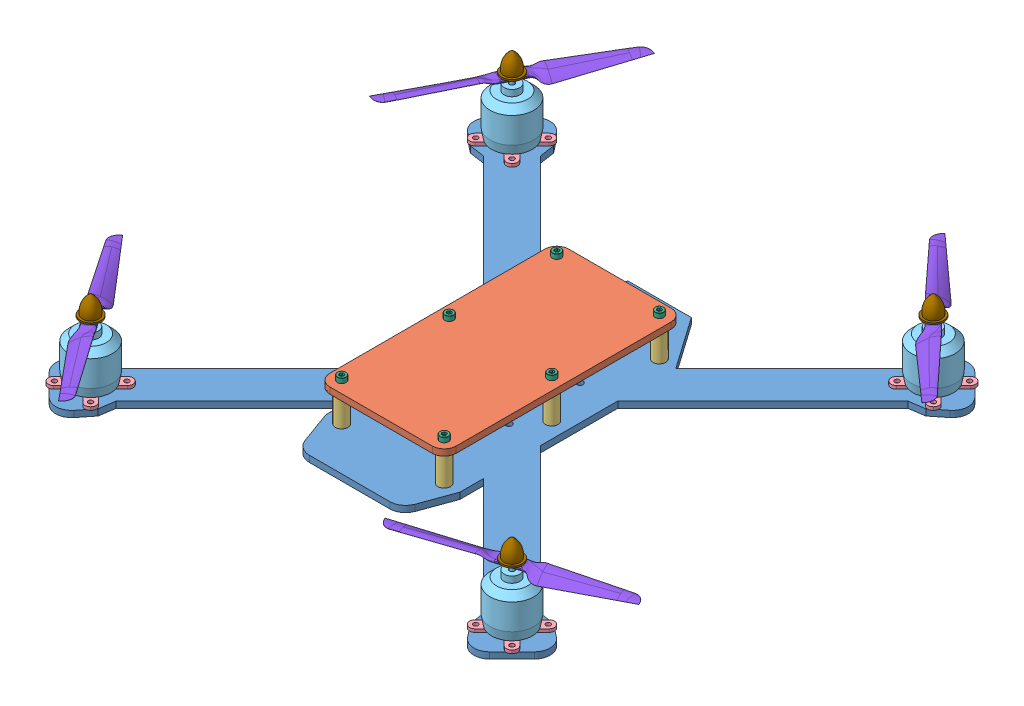
SolidWorks assembly DroneQuadV2, configuration Predeterminado. Lengths in mm.
Overall size (377.34 57 387.09).
52 component instances, 9 part files, 113 mates.
Components (placement in the parent):
- DroneChassisV2-1: DroneChassisV2 [Predeterminado] at origin size (313.31 4 313.31)
- TapaDronV2-1: TapaDronV2 [Predeterminado] at (0 24 0) size (80 4 151.37)
- Soporte-1: Soporte [Predeterminado] at (-32.5 4 -60.9077) x (-0.782804 0 0.622268) z (-0.622268 0 -0.782804) size (8 20 8)
- Soporte-2: Soporte [Predeterminado] at (-32.5 4 7.2764) x (0.196704 0 0.980463) z (-0.980463 0 0.196704) size (8 20 8)
- Soporte-3: Soporte [Predeterminado] at (-32.5 4 75.4605) x (0.051927 0 -0.998651) z (0.998651 0 0.051927) size (8 20 8)
- Soporte-5: Soporte [Predeterminado] at (32.5 4 7.2764) x (0.261502 0 0.965203) z (-0.965203 0 0.261502) size (8 20 8)
- Soporte-6: Soporte [Predeterminado] at (32.5 4 -60.9077) x (0.15369 0 0.988119) z (-0.988119 0 0.15369) size (8 20 8)
- BrushlessMount-1: BrushlessMount [Predeterminado] at (133.527 4 133.527) x (0.707107 0 0.707107) z (-0.707107 0 0.707107) size (40 2 40)
- BrushlessMount-2: BrushlessMount [Predeterminado] at (133.527 4 -133.527) x (0.707107 0 -0.707107) z (0.707107 0 0.707107) size (40 2 40)
- BrushlessMount-3: BrushlessMount [Predeterminado] at (-133.527 4 -133.527) x (0.707107 0 0.707107) z (-0.707107 0 0.707107) size (40 2 40)
- BrushlessMount-4: BrushlessMount [Predeterminado] at (-133.527 4 133.527) x (0.707107 0 -0.707107) z (0.707107 0 0.707107) size (40 2 40)
- MotorBrushless-1: MotorBrushless [Predeterminado] at (-133.527 6 -133.527) x (0.707107 0 0.707107) z (-0.707107 0 0.707107) size (27.7 40 27.7)
- MotorBrushless-2: MotorBrushless [Predeterminado] at (-133.527 6 133.527) x (0.707107 0 -0.707107) z (0.707107 0 0.707107) size (27.7 40 27.7)
- MotorBrushless-3: MotorBrushless [Predeterminado] at (133.527 6 133.527) x (0.707107 0 0.707107) z (-0.707107 0 0.707107) size (27.7 40 27.7)
- MotorBrushless-4: MotorBrushless [Predeterminado] at (133.527 6 -133.527) x (0.707107 0 -0.707107) z (0.707107 0 0.707107) size (27.7 40 27.7)
- Soporte-7: Soporte [Predeterminado] at (32.5 4 75.4605) x (-0.432806 0 0.901487) z (-0.901487 0 -0.432806) size (8 20 8)
- socket head cap screw_iso-2: socket head cap screw_iso [ISO 4762 M3 x 30 - 18N] at (32.5 31 -60.9077) x (0 -1 0) z (0 0 1) size (33 5.5 5.5)
- socket head cap screw_iso-3: socket head cap screw_iso [ISO 4762 M3 x 30 - 18N] at (-32.5 31 -60.9077) x (0 -1 0) z (0 0 1) size (33 5.5 5.5)
- socket head cap screw_iso-4: socket head cap screw_iso [ISO 4762 M3 x 30 - 18N] at (-32.5 31 7.2764) x (0 -1 0) z (0 0 1) size (33 5.5 5.5)
- socket head cap screw_iso-5: socket head cap screw_iso [ISO 4762 M3 x 30 - 18N] at (32.5 31 7.2764) x (0 -1 0) z (0 0 1) size (33 5.5 5.5)
- socket head cap screw_iso-6: socket head cap screw_iso [ISO 4762 M3 x 30 - 18N] at (-32.5 31 75.4605) x (0 -1 0) z (0 0 1) size (33 5.5 5.5)
- socket head cap screw_iso-7: socket head cap screw_iso [ISO 4762 M3 x 30 - 18N] at (32.5 31 75.4605) x (0 -1 0) z (0 0 1) size (33 5.5 5.5)
- socket head cap screw_iso-8: socket head cap screw_iso [ISO 4762 M3 x 5 - 5N] at (-139.1839 -3 139.1839) x (0 1 0) z (0 0 1) size (8 5.5 5.5)
- socket head cap screw_iso-9: socket head cap screw_iso [ISO 4762 M3 x 5 - 5N] at (-140.2445 -3 126.8095) x (0 1 0) z (0 0 1) size (8 5.5 5.5)
- socket head cap screw_iso-10: socket head cap screw_iso [ISO 4762 M3 x 5 - 5N] at (-127.8701 -3 127.8701) x (0 1 0) z (0 0 1) size (8 5.5 5.5)
- socket head cap screw_iso-11: socket head cap screw_iso [ISO 4762 M3 x 5 - 5N] at (-126.8095 -3 140.2445) x (0 1 0) z (0 0 1) size (8 5.5 5.5)
- socket head cap screw_iso-12: socket head cap screw_iso [ISO 4762 M3 x 5 - 5N] at (126.8095 -3 140.2445) x (0 1 0) z (0 0 1) size (8 5.5 5.5)
- socket head cap screw_iso-13: socket head cap screw_iso [ISO 4762 M3 x 5 - 5N] at (127.8701 -3 127.8701) x (0 1 0) z (0 0 1) size (8 5.5 5.5)
- socket head cap screw_iso-14: socket head cap screw_iso [ISO 4762 M3 x 5 - 5N] at (140.2445 -3 126.8095) x (0 1 0) z (0 0 1) size (8 5.5 5.5)
- socket head cap screw_iso-15: socket head cap screw_iso [ISO 4762 M3 x 5 - 5N] at (139.1839 -3 139.1839) x (0 1 0) z (0 0 1) size (8 5.5 5.5)
- socket head cap screw_iso-16: socket head cap screw_iso [ISO 4762 M3 x 5 - 5N] at (126.8095 -3 -140.2445) x (0 1 0) z (0 0 1) size (8 5.5 5.5)
- socket head cap screw_iso-17: socket head cap screw_iso [ISO 4762 M3 x 5 - 5N] at (139.1839 -3 -139.1839) x (0 1 0) z (0 0 1) size (8 5.5 5.5)
- socket head cap screw_iso-18: socket head cap screw_iso [ISO 4762 M3 x 5 - 5N] at (140.2445 -3 -126.8095) x (0 1 0) z (0 0 1) size (8 5.5 5.5)
- socket head cap screw_iso-19: socket head cap screw_iso [ISO 4762 M3 x 5 - 5N] at (127.8701 -3 -127.8701) x (0 1 0) z (0 0 1) size (8 5.5 5.5)
- socket head cap screw_iso-20: socket head cap screw_iso [ISO 4762 M3 x 5 - 5N] at (-127.8701 -3 -127.8701) x (0 1 0) z (0 0 1) size (8 5.5 5.5)
- socket head cap screw_iso-21: socket head cap screw_iso [ISO 4762 M3 x 5 - 5N] at (-140.2445 -3 -126.8095) x (0 1 0) z (0 0 1) size (8 5.5 5.5)
- socket head cap screw_iso-22: socket head cap screw_iso [ISO 4762 M3 x 5 - 5N] at (-139.1839 -3 -139.1839) x (0 1 0) z (0 0 1) size (8 5.5 5.5)
- socket head cap screw_iso-23: socket head cap screw_iso [ISO 4762 M3 x 5 - 5N] at (-126.8095 -3 -140.2445) x (0 1 0) z (0 0 1) size (8 5.5 5.5)
- hex thin nut gradeb_iso-3: hex thin nut gradeb_iso [ISO - 4036 - M3 - N] at (-32.5 -1.8 75.4605) x (1 0 0) z (0 -1 0) size (5.5 6.35 1.8)
- hex thin nut gradeb_iso-4: hex thin nut gradeb_iso [ISO - 4036 - M3 - N] at (-32.5 -1.8 7.2764) x (1 0 0) z (0 -1 0) size (5.5 6.35 1.8)
- hex thin nut gradeb_iso-5: hex thin nut gradeb_iso [ISO - 4036 - M3 - N] at (-32.5 -1.8 -60.9077) x (1 0 0) z (0 -1 0) size (5.5 6.35 1.8)
- hex thin nut gradeb_iso-6: hex thin nut gradeb_iso [ISO - 4036 - M3 - N] at (32.5 -1.8 -60.9077) x (1 0 0) z (0 -1 0) size (5.5 6.35 1.8)
- hex thin nut gradeb_iso-7: hex thin nut gradeb_iso [ISO - 4036 - M3 - N] at (32.5 -1.8 7.2764) x (1 0 0) z (0 -1 0) size (5.5 6.35 1.8)
- hex thin nut gradeb_iso-8: hex thin nut gradeb_iso [ISO - 4036 - M3 - N] at (32.5 -1.8 75.4605) x (1 0 0) z (0 -1 0) size (5.5 6.35 1.8)
- Helice-2: Helice [Predeterminado] at (181.0763 40.4154 -81.6) x (-0.700701 0 -0.713456) z (0.713456 0 -0.700701) size (131.65 5.28 15.65)
- Helice-3: Helice [Predeterminado] at (65.9971 40.4154 153.4533) x (0.948639 0 -0.316362) z (0.316362 0 0.948639) size (131.65 5.28 15.65)
- Helice-4: Helice [Predeterminado] at (-167.1056 40.4154 -71.6414) x (0.445898 0 -0.895084) z (0.895084 0 0.445898) size (131.65 5.28 15.65)
- Helice-5: Helice [Predeterminado] at (-93.7455 40.4154 191.6199) x (-0.593505 0 -0.80483) z (0.80483 0 -0.593505) size (131.65 5.28 15.65)
- Tapon-2: Tapon [Predeterminado] at (133.527 42 133.527) x (0.998266 0 0.058858) z (-0.058858 0 0.998266) size (13 12.5 13)
- Tapon-3: Tapon [Predeterminado] at (133.527 42 -133.527) x (-0.990486 0 0.137614) z (-0.137614 0 -0.990486) size (13 12.5 13)
- Tapon-4: Tapon [Predeterminado] at (-133.527 42 -133.527) x (0.207433 0 -0.978249) z (0.978249 0 0.207433) size (13 12.5 13)
- Tapon-5: Tapon [Predeterminado] at (-133.527 42 133.527) x (0.999811 0 -0.01946) z (0.01946 0 0.999811) size (13 12.5 13)
Mates (geometry in assembly coordinates):
- Concéntrica32: concentric aligned: cylinder of DroneChassisV2-1 through (32.5 4 75.4605) axis (0 -1 0) radius 2; cylinder of TapaDronV2-1 through (32.5 28 75.4605) axis (0 -1 0) radius 2
- Concéntrica2: concentric aligned: cylinder of DroneChassisV2-1 through (-32.5 4 -60.9077) axis (0 -1 0) radius 2; cylinder of TapaDronV2-1 through (-32.5 28 -60.9077) axis (0 -1 0) radius 2
- Concéntrica3: concentric aligned: cylinder of DroneChassisV2-1 through (-32.5 4 -60.9077) axis (0 -1 0) radius 2; cylinder of Soporte-1 through (-32.5 24 -60.9077) axis (0 -1 0) radius 4
- Coincidente1: coincident anti-aligned: plane of DroneChassisV2-1 through (-146.6568 4 132.5147) normal (0 1 0); plane of Soporte-1 through (-32.5 4 -60.9077) normal (0 -1 0)
- Coincidente2: coincident anti-aligned: plane of TapaDronV2-1 through (0 24 0) normal (0 -1 0); plane of Soporte-1 through (-32.5 24 -60.9077) normal (0 1 0)
- Concéntrica4: concentric aligned: cylinder of DroneChassisV2-1 through (-32.5 4 7.2764) axis (0 -1 0) radius 2; cylinder of Soporte-2 through (-32.5 24 7.2764) axis (0 -1 0) radius 2.5
- Coincidente3: coincident anti-aligned: plane of DroneChassisV2-1 through (-146.6568 4 132.5147) normal (0 1 0); plane of Soporte-2 through (-32.5 4 7.2764) normal (0 -1 0)
- Coincidente4: coincident anti-aligned: plane of TapaDronV2-1 through (0 24 0) normal (0 -1 0); plane of Soporte-2 through (-32.5 24 7.2764) normal (0 1 0)
- Concéntrica5: concentric aligned: cylinder of DroneChassisV2-1 through (-32.5 4 75.4605) axis (0 -1 0) radius 2; cylinder of Soporte-3 through (-32.5 24 75.4605) axis (0 -1 0) radius 2.5
- Coincidente5: coincident anti-aligned: plane of DroneChassisV2-1 through (-146.6568 4 132.5147) normal (0 1 0); plane of Soporte-3 through (-32.5 4 75.4605) normal (0 -1 0)
- Concéntrica7: concentric aligned: cylinder of DroneChassisV2-1 through (32.5 4 7.2764) axis (0 -1 0) radius 2; cylinder of Soporte-5 through (32.5 24 7.2764) axis (0 -1 0) radius 2.5
- Coincidente7: coincident anti-aligned: plane of DroneChassisV2-1 through (-146.6568 4 132.5147) normal (0 1 0); plane of Soporte-5 through (32.5 4 7.2764) normal (0 -1 0)
- Concéntrica9: concentric anti-aligned: circle of DroneChassisV2-1; cylinder of Soporte-6 through (32.5 24 -60.9077) axis (0 -1 0) radius 2.5
- Coincidente9: coincident anti-aligned: plane of DroneChassisV2-1 through (-146.6568 4 132.5147) normal (0 1 0); plane of Soporte-6 through (32.5 4 -60.9077) normal (0 -1 0)
- Concéntrica10: concentric anti-aligned: cylinder of DroneChassisV2-1 through (140.2445 4 126.8095) axis (0 -1 0) radius 2; circle of BrushlessMount-1
- Concéntrica11: concentric aligned: cylinder of DroneChassisV2-1 through (126.8095 4 140.2445) axis (0 -1 0) radius 2; cylinder of BrushlessMount-1 through (126.8095 6 140.2445) axis (0 -1 0) radius 1.5
- Concéntrica12: concentric aligned: cylinder of DroneChassisV2-1 through (127.8701 4 127.8701) axis (0 -1 0) radius 2; cylinder of BrushlessMount-1 through (127.8701 6 127.8701) axis (0 -1 0) radius 1.5
- Coincidente10: coincident anti-aligned: plane of DroneChassisV2-1 through (-146.6568 4 132.5147) normal (0 1 0); plane of BrushlessMount-1 through (133.527 4 121.5062) normal (0 -1 0)
- Concéntrica15: concentric aligned: cylinder of DroneChassisV2-1 through (126.8095 4 -140.2445) axis (0 -1 0) radius 2; cylinder of BrushlessMount-2 through (126.8095 6 -140.2445) axis (0 -1 0) radius 1.5
- Concéntrica16: concentric aligned: cylinder of DroneChassisV2-1 through (140.2445 4 -126.8095) axis (0 -1 0) radius 2; cylinder of BrushlessMount-2 through (140.2445 6 -126.8095) axis (0 -1 0) radius 1.5
- Concéntrica17: concentric anti-aligned: cylinder of DroneChassisV2-1 through (-126.8095 4 -140.2445) axis (0 -1 0) radius 2; circle of BrushlessMount-3
- Concéntrica18: concentric aligned: circle of DroneChassisV2-1; circle of BrushlessMount-3
- Concéntrica19: concentric aligned: cylinder of DroneChassisV2-1 through (-140.2445 4 126.8095) axis (0 -1 0) radius 2; cylinder of BrushlessMount-4 through (-140.2445 6 126.8095) axis (0 -1 0) radius 1.5
- Concéntrica20: concentric aligned: circle of DroneChassisV2-1; circle of BrushlessMount-4
- Coincidente11: coincident anti-aligned: plane of DroneChassisV2-1 through (-146.6568 4 132.5147) normal (0 1 0); plane of BrushlessMount-4 through (-145.5478 4 133.527) normal (0 -1 0)
- Coincidente12: coincident anti-aligned: plane of DroneChassisV2-1 through (-146.6568 4 132.5147) normal (0 1 0); plane of BrushlessMount-2 through (121.5062 4 -133.527) normal (0 -1 0)
- Coincidente13: coincident anti-aligned: plane of DroneChassisV2-1 through (-146.6568 4 132.5147) normal (0 1 0); plane of BrushlessMount-3 through (-133.527 4 -145.5478) normal (0 -1 0)
- Concéntrica21: concentric aligned: cylinder of BrushlessMount-3 through (-126.8095 6 -140.2445) axis (0 -1 0) radius 1.5; cylinder of MotorBrushless-1 through (-126.8095 10 -140.2445) axis (0 -1 0) radius 2.5
- Concéntrica22: concentric aligned: cylinder of BrushlessMount-3 through (-140.2445 6 -126.8095) axis (0 -1 0) radius 1.5; cylinder of MotorBrushless-1 through (-140.2445 10 -126.8095) axis (0 -1 0) radius 2.5
- Coincidente14: coincident anti-aligned: plane of BrushlessMount-3 through (-133.527 6 -145.5478) normal (0 1 0); plane of MotorBrushless-1 through (-133.527 6 -133.527) normal (0 -1 0)
- Concéntrica23: concentric anti-aligned: circle of BrushlessMount-4; circle of MotorBrushless-2
- Concéntrica24: concentric anti-aligned: circle of BrushlessMount-4; circle of MotorBrushless-2
- Coincidente15: coincident anti-aligned: plane of BrushlessMount-4 through (-145.5478 6 133.527) normal (0 1 0); plane of MotorBrushless-2 through (-133.527 6 133.527) normal (0 -1 0)
- Concéntrica27: concentric aligned: cylinder of BrushlessMount-1 through (126.8095 6 140.2445) axis (0 -1 0) radius 1.5; cylinder of MotorBrushless-3 through (126.8095 10 140.2445) axis (0 -1 0) radius 2.5
- Concéntrica28: concentric aligned: cylinder of BrushlessMount-1 through (140.2445 6 126.8095) axis (0 -1 0) radius 1.5; cylinder of MotorBrushless-3 through (140.2445 10 126.8095) axis (0 -1 0) radius 2.5
- Coincidente16: coincident anti-aligned: plane of BrushlessMount-1 through (133.527 6 121.5062) normal (0 1 0); plane of MotorBrushless-3 through (133.527 6 133.527) normal (0 -1 0)
- Concéntrica29: concentric anti-aligned: circle of BrushlessMount-2; cylinder of MotorBrushless-4 through (126.8095 10 -140.2445) axis (0 -1 0) radius 2.5
- Concéntrica31: concentric aligned: cylinder of BrushlessMount-2 through (140.2445 6 -126.8095) axis (0 -1 0) radius 1.5; cylinder of MotorBrushless-4 through (140.2445 10 -126.8095) axis (0 -1 0) radius 2.5
- Coincidente17: coincident anti-aligned: plane of BrushlessMount-2 through (121.5062 6 -133.527) normal (0 1 0); plane of MotorBrushless-4 through (133.527 6 -133.527) normal (0 -1 0)
- Concéntrica33: concentric anti-aligned: cylinder of DroneChassisV2-1 through (32.5 4 75.4605) axis (0 -1 0) radius 2; circle of Soporte-7
- Coincidente18: coincident anti-aligned: plane of DroneChassisV2-1 through (-146.6568 4 132.5147) normal (0 1 0); plane of Soporte-7 through (32.5 4 75.4605) normal (0 -1 0)
- Concéntrica36: concentric anti-aligned: cylinder of TapaDronV2-1 through (32.5 28 -60.9077) axis (0 -1 0) radius 2; cylinder of socket head cap screw_iso-2 through (32.5 62.75 -60.9077) axis (0 1 0) radius 2.75
- Coincidente22: coincident anti-aligned: plane of TapaDronV2-1 through (0 28 0) normal (0 1 0); plane of socket head cap screw_iso-2 through (35.25 28 -60.9077) normal (0 -1 0)
- Concéntrica37: concentric anti-aligned: cylinder of TapaDronV2-1 through (-32.5 28 -60.9077) axis (0 -1 0) radius 2; cylinder of socket head cap screw_iso-3 through (-32.5 62.75 -60.9077) axis (0 1 0) radius 2.75
- Coincidente24: coincident anti-aligned: plane of TapaDronV2-1 through (0 28 0) normal (0 1 0); plane of socket head cap screw_iso-3 through (-29.75 28 -60.9077) normal (0 -1 0)
- Concéntrica38: concentric anti-aligned: cylinder of TapaDronV2-1 through (-32.5 28 7.2764) axis (0 -1 0) radius 2; cylinder of socket head cap screw_iso-4 through (-32.5 62.75 7.2764) axis (0 1 0) radius 2.75
- Coincidente25: coincident anti-aligned: plane of TapaDronV2-1 through (0 28 0) normal (0 1 0); plane of socket head cap screw_iso-4 through (-29.75 28 7.2764) normal (0 -1 0)
- Concéntrica39: concentric anti-aligned: cylinder of TapaDronV2-1 through (32.5 28 7.2764) axis (0 -1 0) radius 2; cylinder of socket head cap screw_iso-5 through (32.5 62.75 7.2764) axis (0 1 0) radius 2.75
- Coincidente26: coincident anti-aligned: plane of TapaDronV2-1 through (0 28 0) normal (0 1 0); plane of socket head cap screw_iso-5 through (35.25 28 7.2764) normal (0 -1 0)
- Concéntrica40: concentric anti-aligned: cylinder of TapaDronV2-1 through (-32.5 28 75.4605) axis (0 -1 0) radius 2; cylinder of socket head cap screw_iso-6 through (-32.5 62.75 75.4605) axis (0 1 0) radius 2.75
- Coincidente27: coincident anti-aligned: plane of TapaDronV2-1 through (0 28 0) normal (0 1 0); plane of socket head cap screw_iso-6 through (-29.75 28 75.4605) normal (0 -1 0)
- Concéntrica41: concentric anti-aligned: cylinder of TapaDronV2-1 through (32.5 28 75.4605) axis (0 -1 0) radius 2; cylinder of socket head cap screw_iso-7 through (32.5 62.75 75.4605) axis (0 1 0) radius 2.75
- Coincidente28: coincident anti-aligned: plane of TapaDronV2-1 through (0 28 0) normal (0 1 0); plane of socket head cap screw_iso-7 through (35.25 28 75.4605) normal (0 -1 0)
- Concéntrica42: concentric aligned: cylinder of DroneChassisV2-1 through (-139.1839 4 139.1839) axis (0 -1 0) radius 2; cylinder of socket head cap screw_iso-8 through (-139.1839 -34.75 139.1839) axis (0 -1 0) radius 2.75
- Coincidente29: coincident anti-aligned: plane of DroneChassisV2-1 through (-146.6568 0 132.5147) normal (0 -1 0); plane of socket head cap screw_iso-8 through (-141.9339 0 139.1839) normal (0 1 0)
- Concéntrica43: concentric aligned: cylinder of DroneChassisV2-1 through (-140.2445 4 126.8095) axis (0 -1 0) radius 2; cylinder of socket head cap screw_iso-9 through (-140.2445 -34.75 126.8095) axis (0 -1 0) radius 2.75
- Coincidente30: coincident anti-aligned: plane of DroneChassisV2-1 through (-146.6568 0 132.5147) normal (0 -1 0); plane of socket head cap screw_iso-9 through (-142.9945 0 126.8095) normal (0 1 0)
- Concéntrica44: concentric aligned: cylinder of DroneChassisV2-1 through (-127.8701 4 127.8701) axis (0 -1 0) radius 2; cylinder of socket head cap screw_iso-10 through (-127.8701 -34.75 127.8701) axis (0 -1 0) radius 2.75
- Coincidente31: coincident anti-aligned: plane of DroneChassisV2-1 through (-146.6568 0 132.5147) normal (0 -1 0); plane of socket head cap screw_iso-10 through (-130.6201 0 127.8701) normal (0 1 0)
- Concéntrica45: concentric aligned: cylinder of DroneChassisV2-1 through (-126.8095 4 140.2445) axis (0 -1 0) radius 2; cylinder of socket head cap screw_iso-11 through (-126.8095 -34.75 140.2445) axis (0 -1 0) radius 2.75
- Coincidente32: coincident anti-aligned: plane of DroneChassisV2-1 through (-146.6568 0 132.5147) normal (0 -1 0); plane of socket head cap screw_iso-11 through (-129.5595 0 140.2445) normal (0 1 0)
- Concéntrica46: concentric aligned: cylinder of DroneChassisV2-1 through (126.8095 4 140.2445) axis (0 -1 0) radius 2; cylinder of socket head cap screw_iso-12 through (126.8095 -34.75 140.2445) axis (0 -1 0) radius 2.75
- Coincidente33: coincident anti-aligned: plane of DroneChassisV2-1 through (-146.6568 0 132.5147) normal (0 -1 0); plane of socket head cap screw_iso-12 through (124.0595 0 140.2445) normal (0 1 0)
- Concéntrica47: concentric aligned: cylinder of DroneChassisV2-1 through (127.8701 4 127.8701) axis (0 -1 0) radius 2; cylinder of socket head cap screw_iso-13 through (127.8701 -34.75 127.8701) axis (0 -1 0) radius 2.75
- Coincidente34: coincident anti-aligned: plane of DroneChassisV2-1 through (-146.6568 0 132.5147) normal (0 -1 0); plane of socket head cap screw_iso-13 through (125.1201 0 127.8701) normal (0 1 0)
- Concéntrica48: concentric aligned: cylinder of DroneChassisV2-1 through (140.2445 4 126.8095) axis (0 -1 0) radius 2; cylinder of socket head cap screw_iso-14 through (140.2445 -34.75 126.8095) axis (0 -1 0) radius 2.75
- Coincidente35: coincident anti-aligned: plane of DroneChassisV2-1 through (-146.6568 0 132.5147) normal (0 -1 0); plane of socket head cap screw_iso-14 through (137.4945 0 126.8095) normal (0 1 0)
- Concéntrica49: concentric aligned: cylinder of DroneChassisV2-1 through (139.1839 4 139.1839) axis (0 -1 0) radius 2; cylinder of socket head cap screw_iso-15 through (139.1839 -34.75 139.1839) axis (0 -1 0) radius 2.75
- Coincidente36: coincident anti-aligned: plane of DroneChassisV2-1 through (-146.6568 0 132.5147) normal (0 -1 0); plane of socket head cap screw_iso-15 through (136.4339 0 139.1839) normal (0 1 0)
- Concéntrica50: concentric aligned: cylinder of DroneChassisV2-1 through (126.8095 4 -140.2445) axis (0 -1 0) radius 2; cylinder of socket head cap screw_iso-16 through (126.8095 -34.75 -140.2445) axis (0 -1 0) radius 2.75
- Coincidente37: coincident anti-aligned: plane of DroneChassisV2-1 through (-146.6568 0 132.5147) normal (0 -1 0); plane of socket head cap screw_iso-16 through (124.0595 0 -140.2445) normal (0 1 0)
- Concéntrica51: concentric aligned: cylinder of DroneChassisV2-1 through (139.1839 4 -139.1839) axis (0 -1 0) radius 2; cylinder of socket head cap screw_iso-17 through (139.1839 -34.75 -139.1839) axis (0 -1 0) radius 2.75
- Coincidente38: coincident anti-aligned: plane of DroneChassisV2-1 through (-146.6568 0 132.5147) normal (0 -1 0); plane of socket head cap screw_iso-17 through (136.4339 0 -139.1839) normal (0 1 0)
- Concéntrica52: concentric aligned: cylinder of DroneChassisV2-1 through (140.2445 4 -126.8095) axis (0 -1 0) radius 2; cylinder of socket head cap screw_iso-18 through (140.2445 -34.75 -126.8095) axis (0 -1 0) radius 2.75
- Coincidente39: coincident anti-aligned: plane of DroneChassisV2-1 through (-146.6568 0 132.5147) normal (0 -1 0); plane of socket head cap screw_iso-18 through (137.4945 0 -126.8095) normal (0 1 0)
- Concéntrica53: concentric aligned: cylinder of DroneChassisV2-1 through (127.8701 4 -127.8701) axis (0 -1 0) radius 2; cylinder of socket head cap screw_iso-19 through (127.8701 -34.75 -127.8701) axis (0 -1 0) radius 2.75
- Coincidente40: coincident anti-aligned: plane of DroneChassisV2-1 through (-146.6568 0 132.5147) normal (0 -1 0); plane of socket head cap screw_iso-19 through (125.1201 0 -127.8701) normal (0 1 0)
- Concéntrica54: concentric aligned: cylinder of DroneChassisV2-1 through (-127.8701 4 -127.8701) axis (0 -1 0) radius 2; cylinder of socket head cap screw_iso-20 through (-127.8701 -34.75 -127.8701) axis (0 -1 0) radius 2.75
- Coincidente41: coincident anti-aligned: plane of DroneChassisV2-1 through (-146.6568 0 132.5147) normal (0 -1 0); plane of socket head cap screw_iso-20 through (-130.6201 0 -127.8701) normal (0 1 0)
- Concéntrica55: concentric aligned: cylinder of DroneChassisV2-1 through (-140.2445 4 -126.8095) axis (0 -1 0) radius 2; cylinder of socket head cap screw_iso-21 through (-140.2445 -34.75 -126.8095) axis (0 -1 0) radius 2.75
- Coincidente42: coincident anti-aligned: plane of DroneChassisV2-1 through (-146.6568 0 132.5147) normal (0 -1 0); plane of socket head cap screw_iso-21 through (-142.9945 0 -126.8095) normal (0 1 0)
- Concéntrica56: concentric aligned: cylinder of DroneChassisV2-1 through (-139.1839 4 -139.1839) axis (0 -1 0) radius 2; cylinder of socket head cap screw_iso-22 through (-139.1839 -34.75 -139.1839) axis (0 -1 0) radius 2.75
- Coincidente43: coincident anti-aligned: plane of DroneChassisV2-1 through (-146.6568 0 132.5147) normal (0 -1 0); plane of socket head cap screw_iso-22 through (-141.9339 0 -139.1839) normal (0 1 0)
- Concéntrica57: concentric aligned: cylinder of DroneChassisV2-1 through (-126.8095 4 -140.2445) axis (0 -1 0) radius 2; cylinder of socket head cap screw_iso-23 through (-126.8095 -34.75 -140.2445) axis (0 -1 0) radius 2.75
- Coincidente44: coincident anti-aligned: plane of DroneChassisV2-1 through (-146.6568 0 132.5147) normal (0 -1 0); plane of socket head cap screw_iso-23 through (-129.5595 0 -140.2445) normal (0 1 0)
- Concéntrica62: concentric aligned: cylinder of DroneChassisV2-1 through (-32.5 4 75.4605) axis (0 -1 0) radius 2; cylinder of hex thin nut gradeb_iso-3 through (-32.5 23.2375 75.4605) axis (0 -1 0) radius 1.5
- Coincidente49: coincident anti-aligned: plane of DroneChassisV2-1 through (-146.6568 0 132.5147) normal (0 -1 0); plane of hex thin nut gradeb_iso-3 through (-32.5 0 78.6359) normal (0 1 0)
- Concéntrica63: concentric aligned: cylinder of DroneChassisV2-1 through (-32.5 4 7.2764) axis (0 -1 0) radius 2; cylinder of hex thin nut gradeb_iso-4 through (-32.5 23.2375 7.2764) axis (0 -1 0) radius 1.5
- Coincidente50: coincident anti-aligned: plane of DroneChassisV2-1 through (-146.6568 0 132.5147) normal (0 -1 0); plane of hex thin nut gradeb_iso-4 through (-32.5 0 10.4519) normal (0 1 0)
- Concéntrica64: concentric aligned: cylinder of DroneChassisV2-1 through (-32.5 4 -60.9077) axis (0 -1 0) radius 2; cylinder of hex thin nut gradeb_iso-5 through (-32.5 23.2375 -60.9077) axis (0 -1 0) radius 1.5
- Coincidente51: coincident anti-aligned: plane of DroneChassisV2-1 through (-146.6568 0 132.5147) normal (0 -1 0); plane of hex thin nut gradeb_iso-5 through (-32.5 0 -57.7322) normal (0 1 0)
- Concéntrica65: concentric aligned: cylinder of DroneChassisV2-1 through (32.5 4 -60.9077) axis (0 -1 0) radius 2; cylinder of hex thin nut gradeb_iso-6 through (32.5 23.2375 -60.9077) axis (0 -1 0) radius 1.5
- Coincidente52: coincident anti-aligned: plane of DroneChassisV2-1 through (-146.6568 0 132.5147) normal (0 -1 0); plane of hex thin nut gradeb_iso-6 through (32.5 0 -57.7322) normal (0 1 0)
- Concéntrica66: concentric aligned: cylinder of DroneChassisV2-1 through (32.5 4 7.2764) axis (0 -1 0) radius 2; cylinder of hex thin nut gradeb_iso-7 through (32.5 23.2375 7.2764) axis (0 -1 0) radius 1.5
- Coincidente53: coincident anti-aligned: plane of DroneChassisV2-1 through (-146.6568 0 132.5147) normal (0 -1 0); plane of hex thin nut gradeb_iso-7 through (32.5 0 10.4519) normal (0 1 0)
- Concéntrica67: concentric aligned: cylinder of DroneChassisV2-1 through (32.5 4 75.4605) axis (0 -1 0) radius 2; cylinder of hex thin nut gradeb_iso-8 through (32.5 23.2375 75.4605) axis (0 -1 0) radius 1.5
- Coincidente54: coincident anti-aligned: plane of DroneChassisV2-1 through (-146.6568 0 132.5147) normal (0 -1 0); plane of hex thin nut gradeb_iso-8 through (32.5 0 78.6359) normal (0 1 0)
- Concéntrica69: concentric anti-aligned: cylinder of MotorBrushless-4 through (133.527 46 -133.527) axis (0 -1 0) radius 1.5875; cylinder of Helice-2 through (133.527 37.1127 -133.527) axis (0 1 0) radius 1.5
- Concéntrica70: concentric anti-aligned: cylinder of MotorBrushless-3 through (133.527 46 133.527) axis (0 -1 0) radius 1.5875; cylinder of Helice-3 through (133.527 37.1127 133.527) axis (0 1 0) radius 1.5
- Concéntrica71: concentric anti-aligned: cylinder of MotorBrushless-2 through (-133.527 46 133.527) axis (0 -1 0) radius 1.5875; cylinder of Helice-5 through (-133.527 37.1127 133.527) axis (0 1 0) radius 1.5
- Concéntrica72: concentric anti-aligned: cylinder of MotorBrushless-1 through (-133.527 46 -133.527) axis (0 -1 0) radius 1.5875; cylinder of Helice-4 through (-133.527 37.1127 -133.527) axis (0 1 0) radius 1.5
- Coincidente55: coincident aligned: plane of Helice-2 through (125.5003 39.5 -146.1596) normal (0 -1 0); plane of Helice-4 through (-124.2032 39.5 -145.235) normal (0 -1 0)
- Coincidente56: coincident aligned: plane of Helice-2 through (125.5003 39.5 -146.1596) normal (0 -1 0); plane of Helice-3 through (148.4009 39.5 131.8609) normal (0 -1 0)
- Coincidente57: coincident aligned: plane of Helice-3 through (148.4009 39.5 131.8609) normal (0 -1 0); plane of Helice-5 through (-139.6991 39.5 119.8919) normal (0 -1 0)
- Concéntrica74: concentric aligned: cylinder of MotorBrushless-3 through (133.527 46 133.527) axis (0 -1 0) radius 1.5875; cylinder of Tapon-2 through (133.527 46 133.527) axis (0 -1 0) radius 1.55
- Coincidente59: coincident anti-aligned: plane of Helice-3 through (148.4009 41.5 131.8609) normal (0 1 0); plane of Tapon-2 through (133.527 41.5 133.527) normal (0 -1 0)
- Coincidente60: coincident anti-aligned: plane of MotorBrushless-3 through (133.527 46 133.527) normal (0 1 0); plane of Tapon-2 through (133.527 46 133.527) normal (0 -1 0)
- Coincidente61: coincident anti-aligned: plane of Helice-2 through (141.5537 41.5 -120.8944) normal (0 1 0); plane of Tapon-3 through (133.527 41.5 -133.527) normal (0 -1 0)
- Concéntrica75: concentric aligned: cylinder of MotorBrushless-4 through (133.527 46 -133.527) axis (0 -1 0) radius 1.5875; circle of Tapon-3
- Concéntrica76: concentric aligned: cylinder of MotorBrushless-1 through (-133.527 46 -133.527) axis (0 -1 0) radius 1.5875; circle of Tapon-4
- Coincidente62: coincident anti-aligned: plane of Helice-4 through (-142.8508 41.5 -121.819) normal (0 1 0); plane of Tapon-4 through (-133.527 41.5 -133.527) normal (0 -1 0)
- Concéntrica77: concentric aligned: cylinder of MotorBrushless-2 through (-133.527 46 133.527) axis (0 -1 0) radius 1.5875; circle of Tapon-5
- Coincidente63: coincident anti-aligned: plane of Helice-5 through (-139.6991 41.5 119.8919) normal (0 1 0); plane of Tapon-5 through (-133.527 41.5 133.527) normal (0 -1 0)
